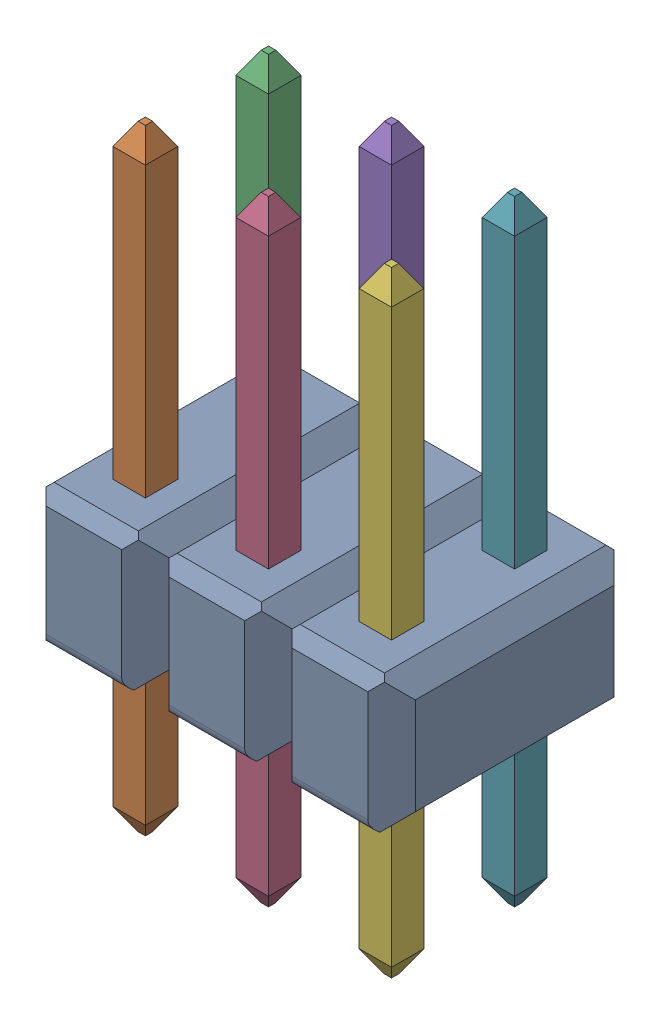
SolidWorks assembly User Library-2x3 TH Pitch 2_54mm, configuration 默认. Lengths in mm.
Overall size (7.62 12.7 5.08).
7 component instances, 2 part files, 0 mates.
Components (placement in the parent):
- header2x3-1: header2x3 [默认] at (0 1.4 0) size (7.62 2.8 5.08)
- pin-1: pin [默认] at (1.29 -3.5 1.29) size (0.67 12.7 0.67)
- pin-2: pin [默认] at (1.29 -3.5 -1.25) size (0.67 12.7 0.67)
- pin-3: pin [默认] at (3.83 -3.5 1.29) size (0.67 12.7 0.67)
- pin-4: pin [默认] at (3.83 -3.5 -1.25) size (0.67 12.7 0.67)
- pin-5: pin [默认] at (6.37 -3.5 1.29) size (0.67 12.7 0.67)
- pin-6: pin [默认] at (6.37 -3.5 -1.25) size (0.67 12.7 0.67)
